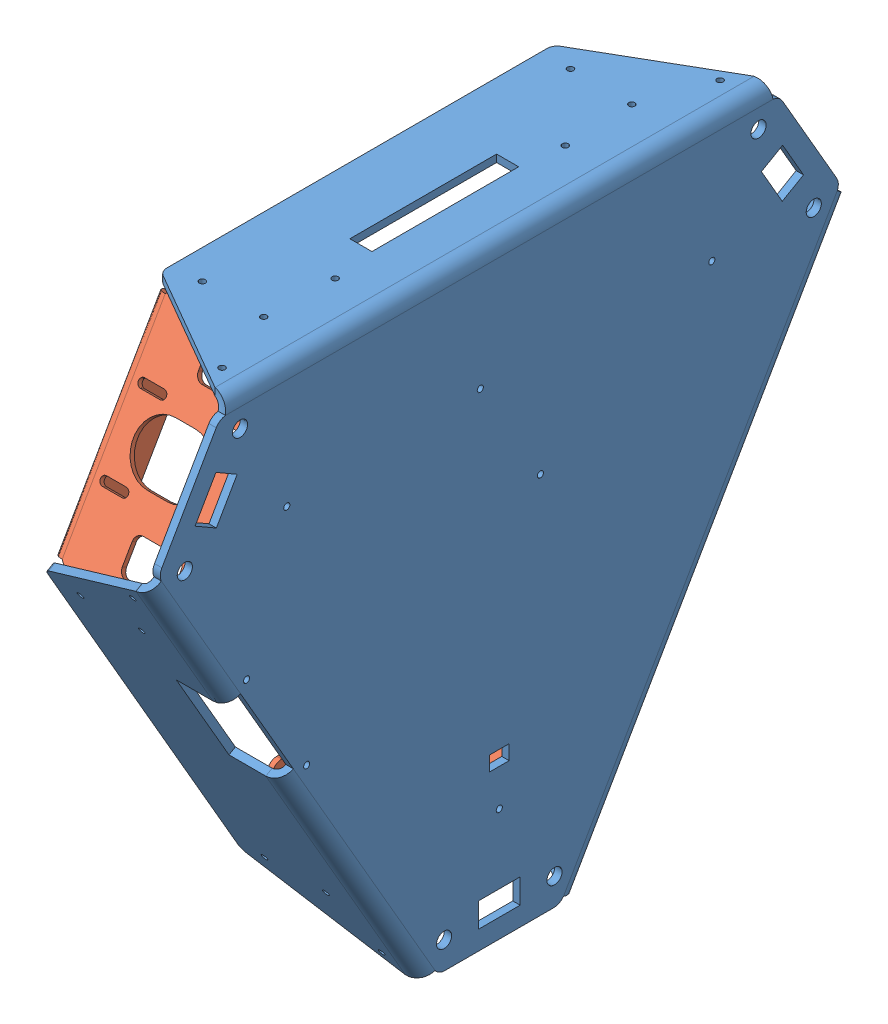
SolidWorks assembly ASM_Base_Metalwork_bottom_2.1.1, configuration Défaut. Lengths in mm.
Overall size (58.35 370.05 356.05).
4 component instances, 2 part files, 4 mates.
Components (placement in the parent):
- Base_v2.1.1-2: Base_v2.1.1 [Défaut] x (1 0 0) z (0 0.866025 0.5) size (58.35 246.65 284.9)
- Base_Motor_bracket_v2.1.1-1: Base_Motor_bracket_v2.1.1 [Défaut] at (-30.5 58.5455 101.4038) x (0 0.866025 -0.5) z (0 -0.5 -0.866025) size (88 55 25)
- Base_Motor_bracket_v2.1.1-2: Base_Motor_bracket_v2.1.1 [Défaut] at (-30.5 -117.091 0) x (0 0 1) z (0 1 0) size (88 55 25)
- Base_Motor_bracket_v2.1.1-3: Base_Motor_bracket_v2.1.1 [Défaut] at (-30.5 58.5455 -101.4038) x (0 -0.866025 -0.5) z (0 -0.5 0.866025) size (88 55 25)
Mates (geometry in assembly coordinates):
- Coïncidente16: coincident: plane of Base_v2.1.1-2 through (0 -48.8253 84.5679) normal (0 0.5 -0.866025); line of Base_Motor_bracket_v2.1.1-1 through (-10 21.4404 125.1359) axis (-1 0 0)
- Coïncidente17: coincident: plane of Base_v2.1.1-2 through (0 97.6506 0) normal (0 -1 0); line of Base_Motor_bracket_v2.1.1-1 through (-52 97.6506 81.1359) axis (1 0 0)
- Coïncidente18: coincident anti-aligned: plane of Base_v2.1.1-2 through (-3 0 0) normal (-1 0 0); plane of Base_Motor_bracket_v2.1.1-1 through (-3 21.4404 125.1359) normal (1 0 0)
- Parallèle3: parallel aligned: plane of Base_v2.1.1-2 through (-3 71.4862 106.8178) normal (0 -0.866025 0.5); plane of Base_Motor_bracket_v2.1.1-1 through (-34.5 69.5053 97.3867) normal (0 -0.866025 0.5)
